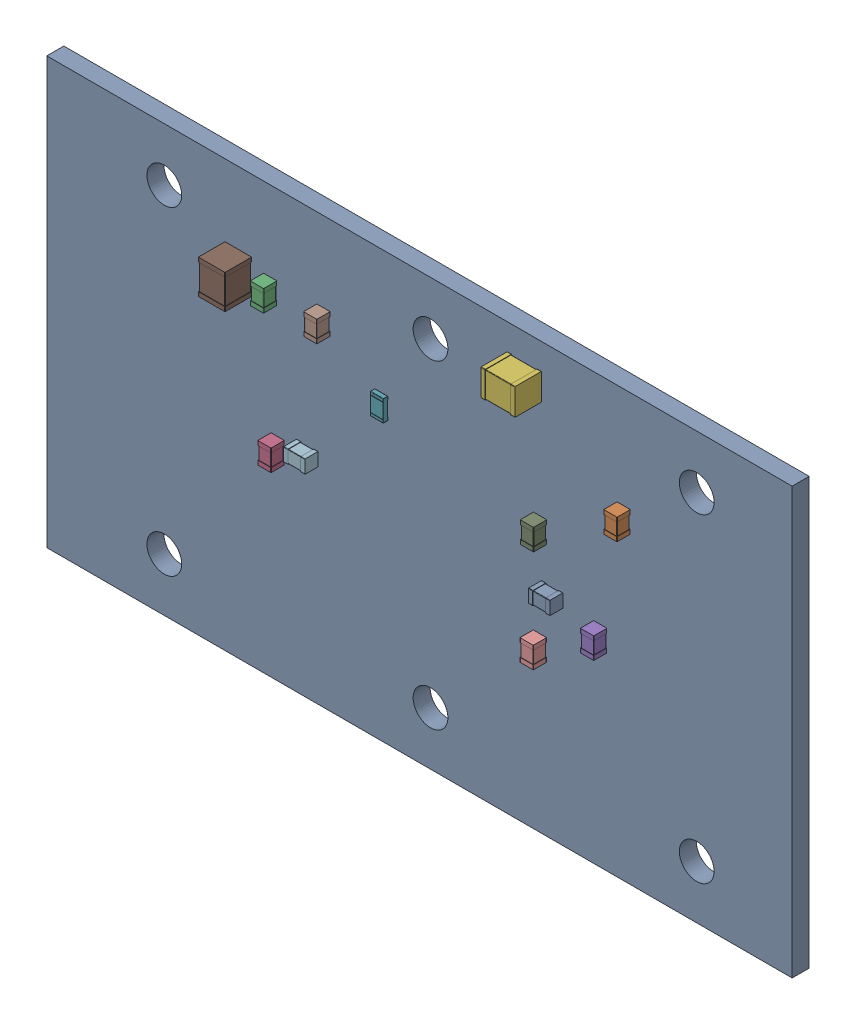
SolidWorks assembly S-Band Amplifier(2), configuration Default. Lengths in mm.
Overall size (70 40 4.15).
25 component instances, 4 part files, 0 mates.
Components (placement in the parent):
- C_0805_2012Metric-1: C_0805_2012Metric [Default] at (91.5 -90 1.65) size (2 1.25 1.25)
  - C_0805_2012Metric-0-1: C_0805_2012Metric-0 [Default] at origin size (2 1.25 1.25)
- C_0805_2012Metric-2: C_0805_2012Metric [Default] at (98.19 -80.45 1.65) x (0 -1 0) z (0 0 1) size (2 1.25 1.25)
  - C_0805_2012Metric-0-1: C_0805_2012Metric-0 [Default] at origin size (2 1.25 1.25)
- C_0805_2012Metric-3: C_0805_2012Metric [Default] at (65 -78.45 1.65) x (0 1 0) z (0 0 1) size (2 1.25 1.25)
  - C_0805_2012Metric-0-1: C_0805_2012Metric-0 [Default] at origin size (2 1.25 1.25)
- C_0805_2012Metric-4: C_0805_2012Metric [Default] at (65.7 -91.075 1.65) x (0 -1 0) z (0 0 1) size (2 1.25 1.25)
  - C_0805_2012Metric-0-1: C_0805_2012Metric-0 [Default] at origin size (2 1.25 1.25)
- C_0805_2012Metric-5: C_0805_2012Metric [Default] at (96 -91.2 1.65) x (0 1 0) z (0 0 1) size (2 1.25 1.25)
  - C_0805_2012Metric-0-1: C_0805_2012Metric-0 [Default] at origin size (2 1.25 1.25)
- C_1210_3225Metric-1: C_1210_3225Metric [Default] at (88.875 -73.63 1.65) x (-1 0 0) z (0 0 1) size (3.2 2.5 2.5)
  - C_1210_3225Metric-1-1: C_1210_3225Metric-1 [Default] at origin size (3.2 2.5 2.5)
- R_0805_2012Metric-1: R_0805_2012Metric [Default] at (75.45 -82.6 1.65) x (0 -1 0) z (0 0 1) size (2 1.2 0.45)
  - R_0805_2012Metric-2-1: R_0805_2012Metric-2 [Default] at origin size (2 1.2 0.45)
- C_0805_2012Metric-6: C_0805_2012Metric [Default] at (70 -78.45 1.65) x (0 1 0) z (0 0 1) size (2 1.25 1.25)
  - C_0805_2012Metric-0-1: C_0805_2012Metric-0 [Default] at origin size (2 1.25 1.25)
- C_0805_2012Metric-7: C_0805_2012Metric [Default] at (90.35 -85.2 1.65) x (0 1 0) z (0 0 1) size (2 1.25 1.25)
  - C_0805_2012Metric-0-1: C_0805_2012Metric-0 [Default] at origin size (2 1.25 1.25)
- C_0805_2012Metric-8: C_0805_2012Metric [Default] at (90.325 -94.8 1.65) x (0 -1 0) z (0 0 1) size (2 1.25 1.25)
  - C_0805_2012Metric-0-1: C_0805_2012Metric-0 [Default] at origin size (2 1.25 1.25)
- C_1210_3225Metric-2: C_1210_3225Metric [Default] at (62 -78.3 1.65) x (0 1 0) z (0 0 1) size (3.2 2.5 2.5)
  - C_1210_3225Metric-1-1: C_1210_3225Metric-1 [Default] at origin size (3.2 2.5 2.5)
- C_0805_2012Metric-9: C_0805_2012Metric [Default] at (68.5 -90 1.65) size (2 1.25 1.25)
  - C_0805_2012Metric-0-1: C_0805_2012Metric-0 [Default] at origin size (2 1.25 1.25)
- S-Band Amplifier_PCB-1: S-Band Amplifier_PCB [Default] at origin size (70 40 1.6)
